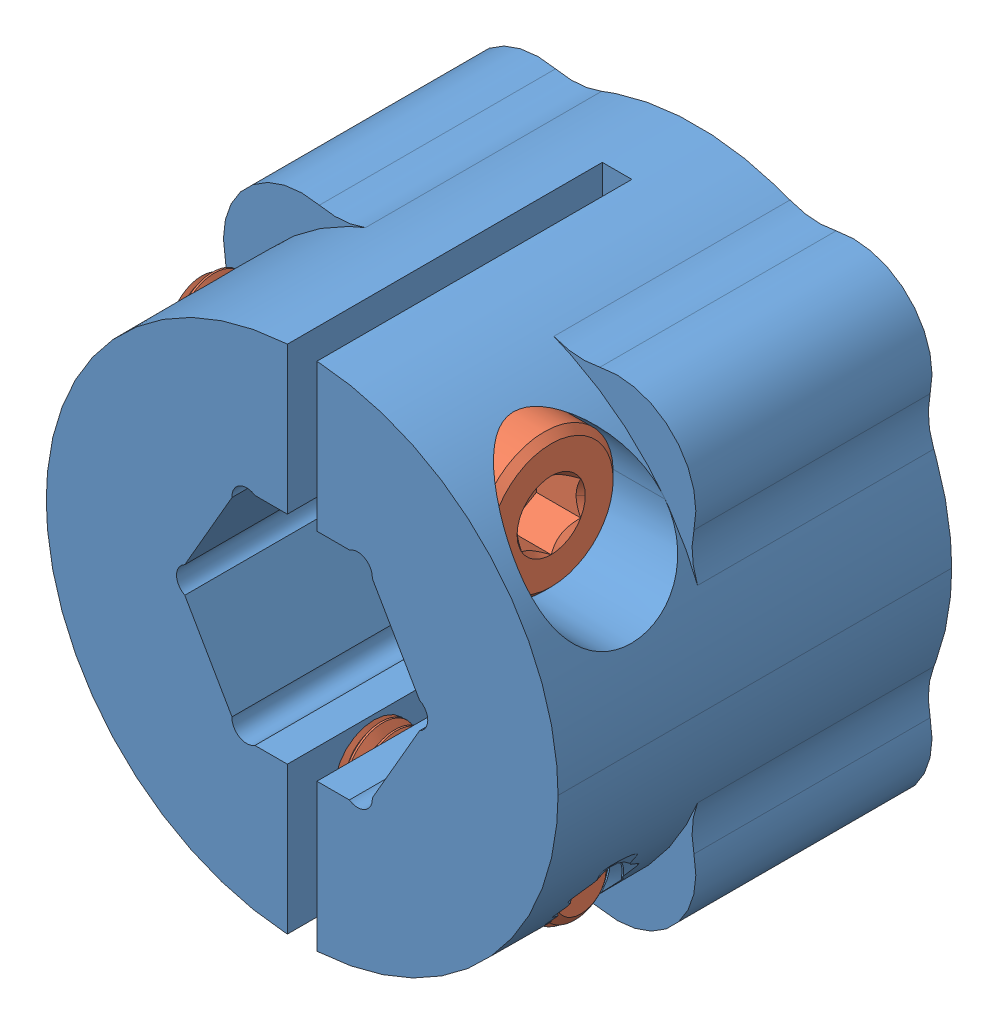
SolidWorks assembly 12mm Hyper Hex Hub 1310-0016-4012, configuration Default. Lengths in mm.
Overall size (26 26 22).
3 component instances, 2 part files, 0 mates.
Components (placement in the parent):
- 1310-0016-4012.STEP-1: 1310-0016-4012.STEP [Default] at (7.7672 18.1012 8.4002) size (26 26 22)
- 2800-0004-0014_90128A207.STEP-1: 2800-0004-0014_90128A207.STEP [Default] at (-1.9828 25.8512 24.0002) x (0 0 1) z (-1 0 0) size (7 7 18.01)
- 2800-0004-0014_90128A207.STEP-2: 2800-0004-0014_90128A207.STEP [Default] at (17.5172 10.3512 24.0002) x (0 0 1) z (1 0 0) size (7 7 18.01)
